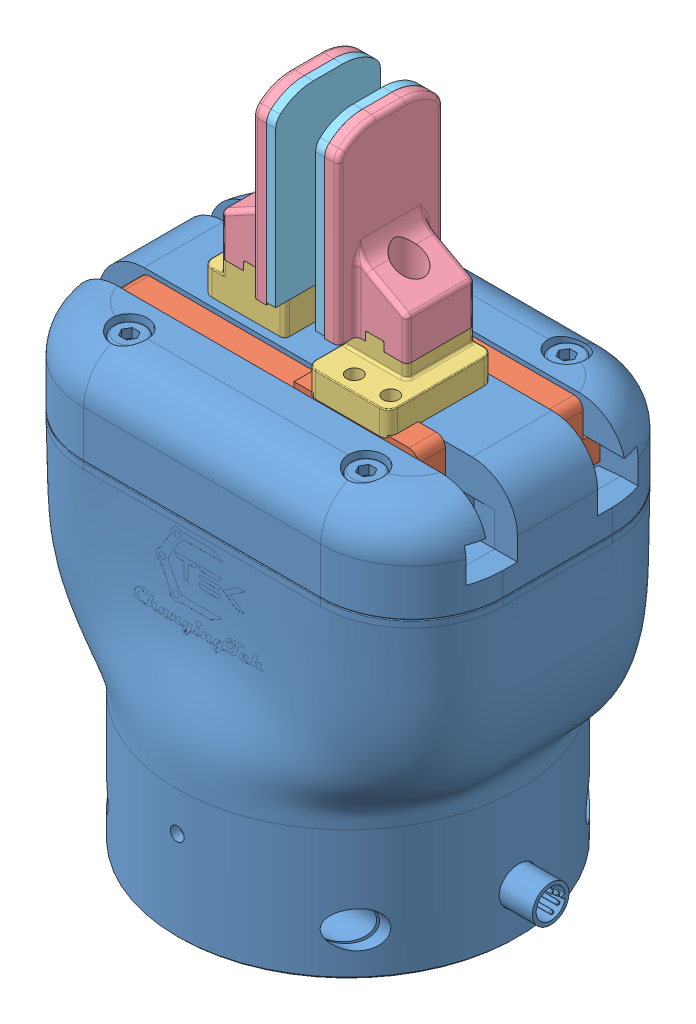
SolidWorks assembly CTP.00_两指平动手(内嵌控制器版)11, configuration 默认. Lengths in mm.
Overall size (92.44 143.8 76.54).
9 component instances, 5 part files, 29 mates.
Components (placement in the parent):
- CTP.00_两指平动手(内嵌控制器版)1-1: CTP.00_两指平动手(内嵌控制器版)1 [默认] at origin size (92.44 95.92 76.54)
- CTP.01.03.01_齿条1-1: CTP.01.03.01_齿条1 [默认] at (-37.6726 10.75 18) x (1 0 0) z (0 1 0) size (67 12.7 15.8)
- CTP.01.03.01_齿条1-3: CTP.01.03.01_齿条1 [默认] at (37.6726 10.75 -18) x (-1 0 0) z (0 1 0) size (67 12.7 15.8)
- CTP.01.04.01_指端座1-1: CTP.01.04.01_指端座1 [默认] at (-15.385 26.05 -4) x (0 0 1) z (-1 0 0) size (23 10.5 18)
- CTP.01.04.01_指端座1-2: CTP.01.04.01_指端座1 [默认] at (15.385 26.05 4) x (0 0 -1) z (1 0 0) size (23 10.5 18)
- CTP.01.04.02_指端1-1: CTP.01.04.02_指端1 [默认] at (7.885 54.3 0) x (0 0 1) z (-1 0 0) size (23 39.5 14)
- CTP.01.04.02_指端1-2: CTP.01.04.02_指端1 [默认] at (-7.885 54.3 0) x (0 0 -1) z (1 0 0) size (23 39.5 14)
- CTP.01.04.03_指垫-1: CTP.01.04.03_指垫 [默认] at (-5.385 54.55 0) x (0 0 1) z (-1 0 0) size (23 39 2)
- CTP.01.04.03_指垫-2: CTP.01.04.03_指垫 [默认] at (5.385 54.55 0) x (0 0 1) z (-1 0 0) size (23 39 2)
Mates (geometry in assembly coordinates):
- 重合1: coincident aligned: plane of CTP.00_两指平动手(内嵌控制器版)1-1 through (0 0 0) normal (0 0 1); plane of assembly through (0 0 0) normal (0 0 1)
- 重合2: coincident aligned: plane of CTP.00_两指平动手(内嵌控制器版)1-1 through (0 0 0) normal (0 1 0); plane of assembly through (0 0 0) normal (0 1 0)
- 重合3: coincident aligned: plane of CTP.00_两指平动手(内嵌控制器版)1-1 through (0 0 0) normal (1 0 0); plane of assembly through (0 0 0) normal (1 0 0)
- LimitDistance2: limit distance = -20 mm aligned: plane of CTP.00_两指平动手(内嵌控制器版)1-1 through (46 25.55 -32) normal (1 0 0); plane of CTP.01.03.01_齿条1-1 through (30.385 10.75 18) normal (1 0 0)
- 距离2: distance = 0.8 mm aligned: plane of CTP.01.03.01_齿条1-1 through (-42.0568 24.75 18) normal (0 1 0); plane of CTP.00_两指平动手(内嵌控制器版)1-1 through (0 25.55 0) normal (0 1 0)
- 距离3: distance = 17 mm aligned: plane of CTP.01.03.01_齿条1-1 through (-40.9992 24.75 15) normal (0 0 1); plane of CTP.00_两指平动手(内嵌控制器版)1-1 through (-46 25.55 32) normal (0 0 1)
- 重合7: coincident aligned: plane of CTP.01.03.01_齿条1-1 through (-42.0568 24.75 18) normal (0 1 0); plane of CTP.01.03.01_齿条1-3 through (42.0568 24.75 -18) normal (0 1 0)
- LimitDistance3: limit distance = -20 mm aligned: plane of CTP.01.03.01_齿条1-3 through (-30.385 10.75 -18) normal (-1 0 0); plane of CTP.00_两指平动手(内嵌控制器版)1-1 through (-46 25.55 -32) normal (-1 0 0)
- 距离6: distance = 17 mm aligned: plane of CTP.01.03.01_齿条1-3 through (40.9992 24.75 -15) normal (0 0 -1); plane of CTP.00_两指平动手(内嵌控制器版)1-1 through (-46 25.55 -32) normal (0 0 -1)
- 重合10: coincident anti-aligned: plane of CTP.01.03.01_齿条1-1 through (-40.9992 24.75 15) normal (0 0 1); plane of CTP.01.04.01_指端座1-2 through (20.0008 26.55 15) normal (0 0 -1)
- 同心1: concentric aligned: cylinder of CTP.01.03.01_齿条1-1 through (9.0008 26.55 12) axis (0 1 0) radius 1.25; cylinder of CTP.01.04.01_指端座1-2 through (9.0008 31.55 12) axis (0 1 0) radius 1.7
- 同心2: concentric aligned: cylinder of CTP.01.03.01_齿条1-1 through (17.0008 26.55 12) axis (0 1 0) radius 1.25; cylinder of CTP.01.04.01_指端座1-2 through (17.0008 31.55 12) axis (0 1 0) radius 1.7
- 重合11: coincident anti-aligned: plane of CTP.01.03.01_齿条1-1 through (-42.0568 26.55 18) normal (0 1 0); plane of CTP.01.04.01_指端座1-2 through (11.0008 26.55 4) normal (0 -1 0)
- 重合13: coincident anti-aligned: plane of CTP.01.03.01_齿条1-3 through (42.0568 26.55 -18) normal (0 1 0); plane of CTP.01.04.01_指端座1-1 through (-11.0008 26.55 -4) normal (0 -1 0)
- 同心5: concentric anti-aligned: cylinder of CTP.01.04.01_指端座1-2 through (9.0008 34.55 0) axis (0 1 0) radius 1.25; cylinder of CTP.01.04.02_指端1-1 through (9.0008 74.05 0) axis (0 -1 0) radius 3.25
- 重合14: coincident anti-aligned: plane of CTP.01.04.01_指端座1-2 through (11.0008 36.55 7.5) normal (1 0 0); plane of CTP.01.04.02_指端1-1 through (11.0008 34.55 -11.5) normal (-1 0 0)
- 重合15: coincident anti-aligned: plane of CTP.01.04.01_指端座1-2 through (11.0008 34.55 4) normal (0 1 0); plane of CTP.01.04.02_指端1-1 through (2.0008 34.55 -11.5) normal (0 -1 0)
- 同心6: concentric anti-aligned: cylinder of CTP.01.04.01_指端座1-1 through (-9.0008 34.55 0) axis (0 1 0) radius 1.25; cylinder of CTP.01.04.02_指端1-2 through (-9.0008 74.05 0) axis (0 -1 0) radius 3.25
- 重合17: coincident anti-aligned: plane of CTP.01.04.01_指端座1-1 through (-11.0008 34.55 -4) normal (0 1 0); plane of CTP.01.04.02_指端1-2 through (-2.0008 34.55 11.5) normal (0 -1 0)
- 重合18: coincident anti-aligned: plane of CTP.01.03.01_齿条1-3 through (40.9992 24.75 -15) normal (0 0 -1); plane of CTP.01.04.01_指端座1-1 through (-20.0008 26.55 -15) normal (0 0 1)
- 同心7: concentric aligned: cylinder of CTP.01.03.01_齿条1-3 through (-17.0008 26.55 -12) axis (0 1 0) radius 1.25; cylinder of CTP.01.04.01_指端座1-1 through (-17.0008 31.55 -12) axis (0 1 0) radius 1.7
- 重合19: coincident anti-aligned: plane of CTP.01.04.01_指端座1-1 through (-7.0008 36.55 -7.5) normal (1 0 0); plane of CTP.01.04.02_指端1-2 through (-7.0008 34.55 11.5) normal (-1 0 0)
- 重合20: coincident anti-aligned: plane of CTP.01.04.02_指端1-2 through (-2.0008 54.3 0) normal (1 0 0); plane of CTP.01.04.03_指垫-1 through (-2.0008 54.55 0) normal (-1 0 0)
- 重合21: coincident aligned: plane of CTP.01.04.02_指端1-2 through (-2.0008 74.05 11.5) normal (0 0 1); plane of CTP.01.04.03_指垫-1 through (-2.0008 74.05 11.5) normal (0 0 1)
- 重合22: coincident aligned: plane of CTP.01.04.02_指端1-2 through (-2.0008 74.05 11.5) normal (0 1 0); plane of CTP.01.04.03_指垫-1 through (-2.0008 74.05 -11.5) normal (0 1 0)
- 重合23: coincident anti-aligned: plane of CTP.01.04.02_指端1-1 through (2.0008 54.3 0) normal (-1 0 0); plane of CTP.01.04.03_指垫-2 through (2.0008 54.55 0) normal (1 0 0)
- 重合24: coincident aligned: plane of CTP.01.04.02_指端1-1 through (2.0008 74.05 11.5) normal (0 0 1); plane of CTP.01.04.03_指垫-2 through (0.0008 74.05 11.5) normal (0 0 1)
- 重合25: coincident aligned: plane of CTP.01.04.02_指端1-1 through (2.0008 74.05 -11.5) normal (0 1 0); plane of CTP.01.04.03_指垫-2 through (0.0008 74.05 -11.5) normal (0 1 0)
- 对称1: symmetric aligned: plane of ? through (-0.0008 54.55 0) normal (1 0 0); plane of ? through (0.0008 54.55 0) normal (-1 0 0)
